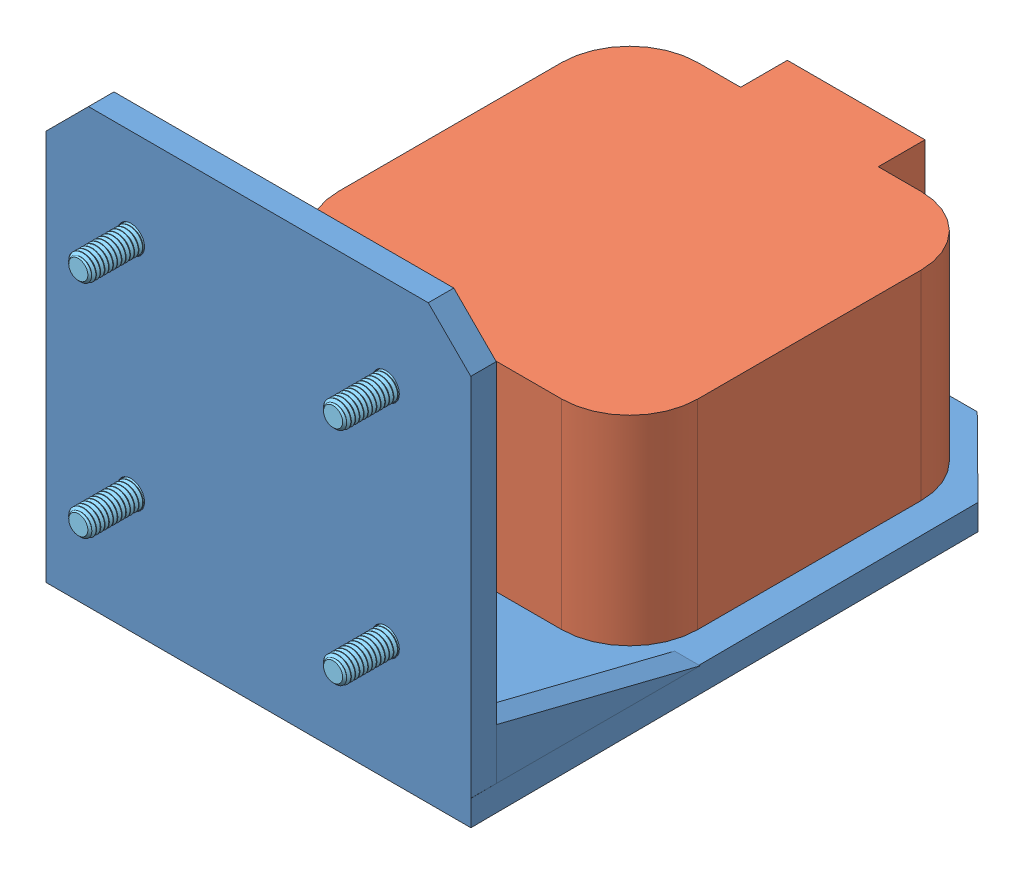
SolidWorks assembly Nema_17_stepper_motor_assembly, configuration Default. Lengths in mm.
Overall size (50 70 76.74).
18 component instances, 5 part files, 35 mates.
Components (placement in the parent):
- Nema_17_stepper_motor_mount-1: Nema_17_stepper_motor_mount [Default] at (45.7083 8.8532 12.0816) size (50 51 69.19)
- Nema_17_stepper_motor-1: Nema_17_stepper_motor [Default] at (-0.7228 35.3532 11.9316) x (1 0 0) z (0 0 -1) size (42.3 45.5 47.8)
- M3_8mm_98511A729_Aluminum Socket Head Screw (1)-1: M3_8mm_98511A729_Aluminum Socket Head Screw (1) [98511A729] at (35.9272 10.5532 17.5816) x (0 -1 0) z (0.154938 0 0.987924) size (11.32 5.68 5.68)
- M3_8mm_98511A729_Aluminum Socket Head Screw (1)-2: M3_8mm_98511A729_Aluminum Socket Head Screw (1) [98511A729] at (4.9272 10.5532 17.5816) x (0 -1 0) z (-0.275017 0 0.961439) size (11.32 5.68 5.68)
- M3_8mm_98511A729_Aluminum Socket Head Screw (1)-3: M3_8mm_98511A729_Aluminum Socket Head Screw (1) [98511A729] at (4.9272 10.5532 48.5816) x (0 -1 0) z (-0.655595 0 0.755113) size (11.32 5.68 5.68)
- M3_8mm_98511A729_Aluminum Socket Head Screw (1)-4: M3_8mm_98511A729_Aluminum Socket Head Screw (1) [98511A729] at (35.9272 10.5532 48.5816) x (0 -1 0) z (-0.465796 0 0.884892) size (11.32 5.68 5.68)
- M3_95610A330_Nylon Plastic Washer-1: M3_95610A330_Nylon Plastic Washer [95610A330] at (35.9272 8.4532 48.5816) x (-0.448529 0 -0.893768) z (0 -1 0) size (8 8 0.8)
- M3_95610A330_Nylon Plastic Washer-2: M3_95610A330_Nylon Plastic Washer [95610A330] at (4.9272 8.4532 48.5816) x (-0.127733 0 0.991809) z (0 -1 0) size (8 8 0.8)
- M3_95610A330_Nylon Plastic Washer-3: M3_95610A330_Nylon Plastic Washer [95610A330] at (35.9272 8.4532 17.5816) x (-0.806169 0 -0.591686) z (0 -1 0) size (8 8 0.8)
- M3_95610A330_Nylon Plastic Washer-4: M3_95610A330_Nylon Plastic Washer [95610A330] at (4.9272 8.4532 17.5816) x (-0.805358 0 0.592789) z (0 -1 0) size (8 8 0.8)
- M3_10mm_98511A731_Aluminum Socket Head Screw-1: M3_10mm_98511A731_Aluminum Socket Head Screw [98511A731] at (5.4272 48.8532 76.4711) x (0 0 -1) z (0.71539 -0.698725 0) size (13.33 5.68 5.68)
- M3_10mm_98511A731_Aluminum Socket Head Screw-2: M3_10mm_98511A731_Aluminum Socket Head Screw [98511A731] at (35.4109 48.8532 76.4711) x (0 0 -1) z (0.870681 -0.491849 0) size (13.33 5.68 5.68)
- M3_10mm_98511A731_Aluminum Socket Head Screw-3: M3_10mm_98511A731_Aluminum Socket Head Screw [98511A731] at (5.4272 22.8532 76.4711) x (0 0 -1) z (0.868244 -0.496138 0) size (13.33 5.68 5.68)
- M3_10mm_98511A731_Aluminum Socket Head Screw-4: M3_10mm_98511A731_Aluminum Socket Head Screw [98511A731] at (35.4109 22.8532 76.4711) x (0 0 -1) z (0.86364 -0.50411 0) size (13.33 5.68 5.68)
- M3_95610A330_Nylon Plastic Washer-5: M3_95610A330_Nylon Plastic Washer [95610A330] at (5.4272 48.8532 73.3711) x (0.984646 -0.17456 0) z (0 0 1) size (8 8 0.8)
- M3_95610A330_Nylon Plastic Washer-6: M3_95610A330_Nylon Plastic Washer [95610A330] at (35.4109 22.8532 73.3711) size (8 8 0.8)
- M3_95610A330_Nylon Plastic Washer-7: M3_95610A330_Nylon Plastic Washer [95610A330] at (35.4109 48.8532 73.3711) size (8 8 0.8)
- M3_95610A330_Nylon Plastic Washer-8: M3_95610A330_Nylon Plastic Washer [95610A330] at (5.4272 22.8532 73.3711) x (0.394525 -0.918885 0) z (0 0 1) size (8 8 0.8)
Mates (geometry in assembly coordinates):
- Concentric1: concentric anti-aligned: cylinder of Nema_17_stepper_motor_mount-1 through (20.4272 11.8532 33.0816) axis (0 -1 0) radius 11; cylinder of Nema_17_stepper_motor-1 through (20.4272 9.8532 33.0816) axis (0 1 0) radius 11
- Coincident1: coincident anti-aligned: plane of Nema_17_stepper_motor_mount-1 through (45.7083 11.8532 12.0816) normal (0 1 0); plane of Nema_17_stepper_motor-1 through (-0.7228 11.8532 11.9316) normal (0 -1 0)
- Parallel2: parallel anti-aligned: plane of Nema_17_stepper_motor_mount-1 through (-4.5728 59.8532 73.7711) normal (0 0 -1); plane of Nema_17_stepper_motor-1 through (-0.7228 11.8532 54.2316) normal (0 0 1)
- Coincident2: coincident anti-aligned: plane of M3_8mm_98511A729_Aluminum Socket Head Screw (1)-4 through (38.4403 8.0532 49.9044) normal (0 1 0); plane of M3_95610A330_Nylon Plastic Washer-1 through (35.9272 8.0532 48.5816) normal (0 -1 0)
- Concentric2: concentric anti-aligned: cylinder of M3_8mm_98511A729_Aluminum Socket Head Screw (1)-4 through (35.9272 5.0532 48.5816) axis (0 -1 0) radius 1.5; cylinder of M3_95610A330_Nylon Plastic Washer-1 through (35.9272 8.0532 48.5816) axis (0 1 0) radius 1.6
- Concentric3: concentric anti-aligned: cylinder of M3_8mm_98511A729_Aluminum Socket Head Screw (1)-3 through (4.9272 5.0532 48.5816) axis (0 -1 0) radius 1.5; cylinder of M3_95610A330_Nylon Plastic Washer-2 through (4.9272 8.0532 48.5816) axis (0 1 0) radius 1.6
- Coincident3: coincident anti-aligned: plane of M3_8mm_98511A729_Aluminum Socket Head Screw (1)-3 through (7.0718 8.0532 50.4435) normal (0 1 0); plane of M3_95610A330_Nylon Plastic Washer-2 through (4.9272 8.0532 48.5816) normal (0 -1 0)
- Concentric4: concentric anti-aligned: cylinder of M3_8mm_98511A729_Aluminum Socket Head Screw (1)-2 through (4.9272 5.0532 17.5816) axis (0 -1 0) radius 1.5; cylinder of M3_95610A330_Nylon Plastic Washer-4 through (4.9272 8.0532 17.5816) axis (0 1 0) radius 1.6
- Coincident4: coincident anti-aligned: plane of M3_8mm_98511A729_Aluminum Socket Head Screw (1)-2 through (7.6577 8.0532 18.3626) normal (0 1 0); plane of M3_95610A330_Nylon Plastic Washer-4 through (4.9272 8.0532 17.5816) normal (0 -1 0)
- Concentric5: concentric anti-aligned: cylinder of M3_8mm_98511A729_Aluminum Socket Head Screw (1)-1 through (35.9272 5.0532 17.5816) axis (0 -1 0) radius 1.5; cylinder of M3_95610A330_Nylon Plastic Washer-3 through (35.9272 8.0532 17.5816) axis (0 1 0) radius 1.6
- Coincident5: coincident anti-aligned: plane of M3_8mm_98511A729_Aluminum Socket Head Screw (1)-1 through (38.7329 8.0532 17.1416) normal (0 1 0); plane of M3_95610A330_Nylon Plastic Washer-3 through (35.9272 8.0532 17.5816) normal (0 -1 0)
- Concentric6: concentric aligned: cylinder of Nema_17_stepper_motor_mount-1 through (35.9272 11.8532 17.5816) axis (0 -1 0) radius 1.6; cylinder of M3_8mm_98511A729_Aluminum Socket Head Screw (1)-1 through (35.9272 5.0532 17.5816) axis (0 -1 0) radius 1.5
- Coincident6: coincident anti-aligned: plane of Nema_17_stepper_motor_mount-1 through (45.7083 8.8532 12.0816) normal (0 -1 0); plane of M3_95610A330_Nylon Plastic Washer-3 through (35.9272 8.8532 17.5816) normal (0 1 0)
- Concentric7: concentric aligned: cylinder of Nema_17_stepper_motor_mount-1 through (4.9272 11.8532 17.5816) axis (0 -1 0) radius 1.6; cylinder of M3_8mm_98511A729_Aluminum Socket Head Screw (1)-2 through (4.9272 5.0532 17.5816) axis (0 -1 0) radius 1.5
- Coincident7: coincident anti-aligned: plane of Nema_17_stepper_motor_mount-1 through (45.7083 8.8532 12.0816) normal (0 -1 0); plane of M3_95610A330_Nylon Plastic Washer-4 through (4.9272 8.8532 17.5816) normal (0 1 0)
- Concentric8: concentric aligned: cylinder of Nema_17_stepper_motor_mount-1 through (4.9272 11.8532 48.5816) axis (0 -1 0) radius 1.6; cylinder of M3_8mm_98511A729_Aluminum Socket Head Screw (1)-3 through (4.9272 5.0532 48.5816) axis (0 -1 0) radius 1.5
- Coincident9: coincident anti-aligned: plane of Nema_17_stepper_motor_mount-1 through (45.7083 8.8532 12.0816) normal (0 -1 0); plane of M3_95610A330_Nylon Plastic Washer-2 through (4.9272 8.8532 48.5816) normal (0 1 0)
- Concentric9: concentric aligned: cylinder of Nema_17_stepper_motor_mount-1 through (35.9272 11.8532 48.5816) axis (0 -1 0) radius 1.6; cylinder of M3_8mm_98511A729_Aluminum Socket Head Screw (1)-4 through (35.9272 5.0532 48.5816) axis (0 -1 0) radius 1.5
- Coincident10: coincident anti-aligned: plane of Nema_17_stepper_motor_mount-1 through (45.7083 8.8532 12.0816) normal (0 -1 0); plane of M3_95610A330_Nylon Plastic Washer-1 through (35.9272 8.8532 48.5816) normal (0 1 0)
- Concentric10: concentric aligned: cylinder of M3_10mm_98511A731_Aluminum Socket Head Screw-4 through (35.4109 22.8532 69.9711) axis (0 0 -1) radius 1.5; cylinder of M3_95610A330_Nylon Plastic Washer-6 through (35.4109 22.8532 73.7711) axis (0 0 -1) radius 1.6
- Coincident11: coincident anti-aligned: plane of M3_10mm_98511A731_Aluminum Socket Head Screw-4 through (36.8426 25.3059 72.9711) normal (0 0 1); plane of M3_95610A330_Nylon Plastic Washer-6 through (35.4109 22.8532 72.9711) normal (0 0 -1)
- Concentric11: concentric aligned: cylinder of M3_10mm_98511A731_Aluminum Socket Head Screw-3 through (5.4272 22.8532 69.9711) axis (0 0 -1) radius 1.5; cylinder of M3_95610A330_Nylon Plastic Washer-8 through (5.4272 22.8532 73.7711) axis (0 0 -1) radius 1.6
- Coincident12: coincident anti-aligned: plane of M3_10mm_98511A731_Aluminum Socket Head Screw-3 through (6.8363 25.319 72.9711) normal (0 0 1); plane of M3_95610A330_Nylon Plastic Washer-8 through (5.4272 22.8532 72.9711) normal (0 0 -1)
- Concentric12: concentric aligned: cylinder of M3_10mm_98511A731_Aluminum Socket Head Screw-1 through (5.4272 48.8532 69.9711) axis (0 0 -1) radius 1.5; cylinder of M3_95610A330_Nylon Plastic Washer-5 through (5.4272 48.8532 73.7711) axis (0 0 -1) radius 1.6
- Coincident13: coincident anti-aligned: plane of M3_10mm_98511A731_Aluminum Socket Head Screw-1 through (7.4116 50.8849 72.9711) normal (0 0 1); plane of M3_95610A330_Nylon Plastic Washer-5 through (5.4272 48.8532 72.9711) normal (0 0 -1)
- Concentric13: concentric aligned: cylinder of M3_10mm_98511A731_Aluminum Socket Head Screw-2 through (35.4109 48.8532 69.9711) axis (0 0 -1) radius 1.5; cylinder of M3_95610A330_Nylon Plastic Washer-7 through (35.4109 48.8532 73.7711) axis (0 0 -1) radius 1.6
- Coincident14: coincident anti-aligned: plane of M3_10mm_98511A731_Aluminum Socket Head Screw-2 through (36.8078 51.3259 72.9711) normal (0 0 1); plane of M3_95610A330_Nylon Plastic Washer-7 through (35.4109 48.8532 72.9711) normal (0 0 -1)
- Concentric14: concentric aligned: cylinder of Nema_17_stepper_motor_mount-1 through (35.4109 48.8532 73.7711) axis (0 0 -1) radius 1.6; cylinder of M3_10mm_98511A731_Aluminum Socket Head Screw-2 through (35.4109 48.8532 69.9711) axis (0 0 -1) radius 1.5
- Coincident15: coincident anti-aligned: plane of Nema_17_stepper_motor_mount-1 through (-4.5728 59.8532 73.7711) normal (0 0 -1); plane of M3_95610A330_Nylon Plastic Washer-7 through (35.4109 48.8532 73.7711) normal (0 0 1)
- Concentric15: concentric aligned: cylinder of Nema_17_stepper_motor_mount-1 through (35.4109 22.8532 73.7711) axis (0 0 -1) radius 1.6; cylinder of M3_10mm_98511A731_Aluminum Socket Head Screw-4 through (35.4109 22.8532 69.9711) axis (0 0 -1) radius 1.5
- Coincident16: coincident anti-aligned: plane of Nema_17_stepper_motor_mount-1 through (-4.5728 59.8532 73.7711) normal (0 0 -1); plane of M3_95610A330_Nylon Plastic Washer-6 through (35.4109 22.8532 73.7711) normal (0 0 1)
- Concentric16: concentric aligned: cylinder of Nema_17_stepper_motor_mount-1 through (5.4272 22.8532 73.7711) axis (0 0 -1) radius 1.6; cylinder of M3_10mm_98511A731_Aluminum Socket Head Screw-3 through (5.4272 22.8532 69.9711) axis (0 0 -1) radius 1.5
- Coincident17: coincident anti-aligned: plane of Nema_17_stepper_motor_mount-1 through (-4.5728 59.8532 73.7711) normal (0 0 -1); plane of M3_95610A330_Nylon Plastic Washer-8 through (5.4272 22.8532 73.7711) normal (0 0 1)
- Concentric17: concentric aligned: cylinder of Nema_17_stepper_motor_mount-1 through (5.4272 48.8532 73.7711) axis (0 0 -1) radius 1.6; cylinder of M3_10mm_98511A731_Aluminum Socket Head Screw-1 through (5.4272 48.8532 69.9711) axis (0 0 -1) radius 1.5
- Coincident18: coincident anti-aligned: plane of Nema_17_stepper_motor_mount-1 through (-4.5728 59.8532 73.7711) normal (0 0 -1); plane of M3_95610A330_Nylon Plastic Washer-5 through (5.4272 48.8532 73.7711) normal (0 0 1)
